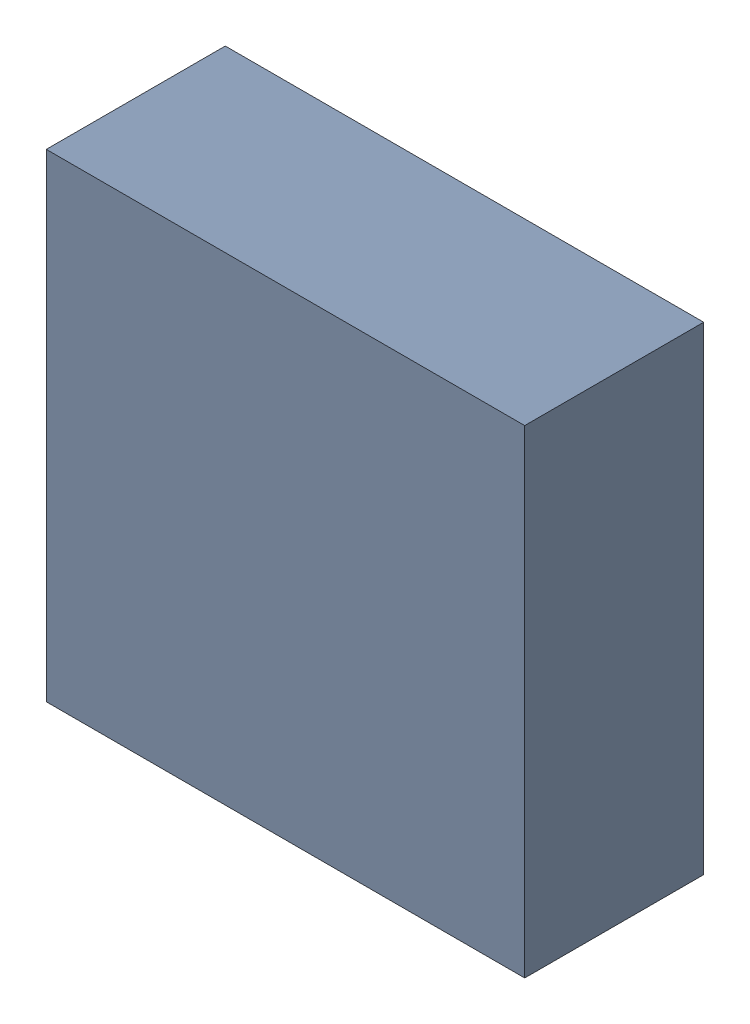
SolidWorks assembly U10, configuration ﾃﾞﾌｫﾙﾄ. Lengths in mm.
Overall size (1.47 1.47 0.55).
2 component instances, 1 part files, 0 mates.
Components (placement in the parent):
- 689262328-1: 689262328 [ﾃﾞﾌｫﾙﾄ] at (67 20.75 0) size (1.47 1.47 0.55)
  - Extruded_39-1: Extruded_39 [ﾃﾞﾌｫﾙﾄ] at origin size (1.47 1.47 0.55)
